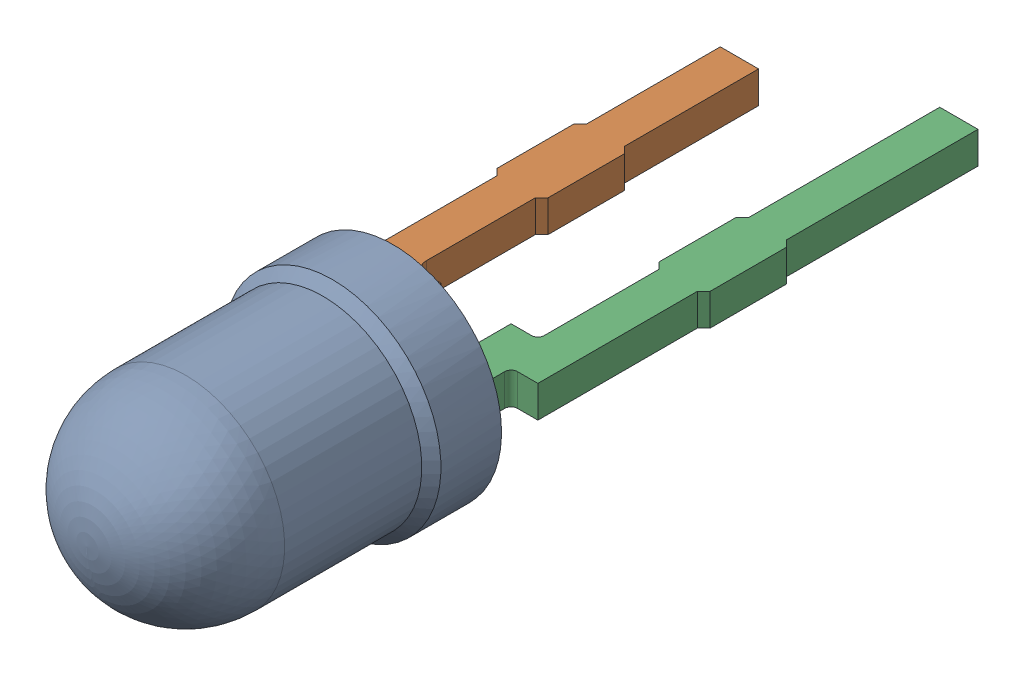
SolidWorks assembly D9, configuration Default. Lengths in mm.
Overall size (3.4 3.4 12.4).
4 component instances, 3 part files, 0 mates.
Components (placement in the parent):
- User_Library-LA_3366_sc-1: User_Library-LA_3366_sc [Default] at (491.0001 310.0001 1.397) size (3.4 3.4 12.4)
  - User_Library-LA_3366_sc_BODY_amber-1: User_Library-LA_3366_sc_BODY_amber [Default] x (1 0 0) z (0 -1 0) size (3.4 4.8 3.4)
  - User_Library-LA_3366_sc_LEAD_A_sc-1: User_Library-LA_3366_sc_LEAD_A_sc [Default] at (0 0.25 0) x (1 0 0) z (0 -1 0) size (1.12 6.7 0.5)
  - User_Library-LA_3366_sc_LEAD_K_sc-1: User_Library-LA_3366_sc_LEAD_K_sc [Default] at (0 -0.25 0) x (-1 0 0) z (0 1 0) size (1.12 7.6 0.5)
